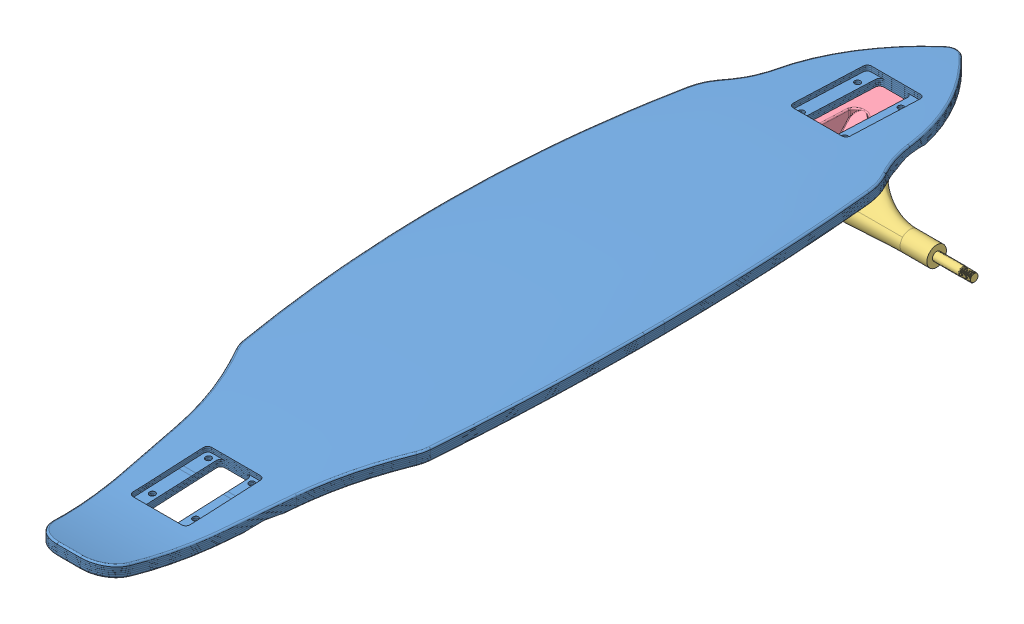
SolidWorks assembly Chamber Complete, configuration Default. Lengths in mm.
Overall size (251.63 119.7 846.49).
12 component instances, 10 part files, 24 mates.
Components (placement in the parent):
- Chamber Deck-2: Chamber Deck [Default] at origin size (203.4 42.87 846.49)
- Truck Cutout-1: Truck Cutout [Default] at (0 15.4335 -251.2196) x (-1 0 0) z (0 0.040365 0.999185) size (652.75 200 200) (hidden)
- Truck Cutout-2: Truck Cutout [Default] at (0 12.2172 374.2126) x (1 0 0) z (0 0.044825 -0.998995) size (652.75 200 200) (hidden)
- Truck-2: Truck [Default] at (27.686 6.0518 -210.5591) x (1 0 0) z (0 -0.0403 -0.999188) size (251.63 82 102.66)
  - Rubber Bushing-1: Rubber Bushing [Default] at (-27.686 9.105 71.5015) x (-0.125245 -0.637726 -0.760012) z (0 0.766044 -0.642788) size (17.78 17.78 15.24)
  - Truck Black-1: Truck Black [Default] at (-27.686 18.8338 63.3381) x (1 0 0) z (0 -0.766044 0.642788) size (251.63 24.69 81.31)
  - Truck Silver-1: Truck Silver [Default] at (-27.686 0 0) x (-1 0 0) z (0 0 -1) size (55.37 68.72 102.66)
  - Large Washer-1: Large Washer [Default] at (-27.686 37.0748 22.445) x (1 0 0) z (0 -0.642788 -0.766044) size (29.97 29.97 4.65)
  - Fat Bushing-1: Fat Bushing [Default] at (-27.686 38.3809 24.0016) x (0.983823 -0.137233 0.115152) z (-0.179144 -0.753652 0.632389) size (25.4 13.76 25.4)
  - Small Bushing-1: Small Bushing [Default] at (-27.686 49.674 37.4601) x (0.221595 -0.747 0.626807) z (0 -0.642788 -0.766044) size (25.4 25.4 13.33)
  - Small Washer-1: Small Washer [Default] at (-27.686 59.5517 49.2319) x (0.99468 -0.07891 0.066213) z (0 0.642788 0.766044) size (23.24 23.24 4.15)
  - 3_8 nut-1: 3_8 nut [94945A218] at (-27.686 59.5517 49.2319) x (1 0 0) z (0 -0.766044 0.642788) size (14.29 7.02 16.5)
Mates (geometry in assembly coordinates):
- Parallel18: parallel: line of Truck Cutout-1 through (23 16.9371 -214) axis (-1 0 0); plane of assembly through (0 0 0) normal (0 0 1)
- Parallel19: parallel: line of Truck Cutout-1 through (23 16.9371 -214) axis (-1 0 0); plane of assembly
- Coincident57: coincident: plane of Truck Cutout-1 through (0 15.4335 -251.2196) normal (-1 0 0); plane of assembly through (0 0 0) normal (1 0 0)
- Coincident58: coincident: face of Chamber Deck-2; point of Truck Cutout-1
- Coincident59: coincident: face of Chamber Deck-2; point of Truck Cutout-1
- Coincident60: coincident: face of Chamber Deck-2; point of Truck Cutout-1
- Parallel20: parallel: line of Truck Cutout-2 through (-23 13.8869 337) axis (1 0 0); plane of assembly
- Parallel21: parallel: line of Truck Cutout-2 through (-23 13.8869 337) axis (1 0 0); plane of assembly
- Coincident63: coincident: plane of Truck Cutout-2 through (0 12.2172 374.2126) normal (1 0 0); plane of assembly through (0 0 0) normal (1 0 0)
- Coincident64: coincident: face of Chamber Deck-2; point of Truck Cutout-2
- Coincident65: coincident: face of Chamber Deck-2; point of Truck Cutout-2
- Coincident66: coincident: face of Chamber Deck-2; point of Truck Cutout-2
- Distance8: distance = 337 mm: line of Truck Cutout-2 through (-23 13.8869 337) axis (1 0 0); plane of assembly
- Distance9: distance = 214 mm: line of Truck Cutout-1 through (23 16.9371 -214) axis (-1 0 0); plane of assembly
- Coincident69: coincident: circle of Chamber Deck-2; circle of ?
- Coincident70: coincident: plane of Chamber Deck-2 through (27 23.6976 341.4442) normal (-1 0 0); plane of ? through (27 8.5922 336.7624) normal (1 0 0)
- Coincident71: coincident: plane of Chamber Deck-2 through (27 26.7675 -218.4004) normal (-1 0 0); plane of ? through (27 12.141 -213.8062) normal (1 0 0)
- Coincident72: coincident: plane of Chamber Deck-2 through (23 11.9796 -217.803) normal (0 0.999185 -0.040365); plane of ? through (0 10.6374 -251.0259) normal (0 -0.999185 0.040365)
- Concentric1: concentric: cylinder of Chamber Deck-2 through (20.55 1.9221 -219.023) axis (0 0.999185 -0.040365) radius 2.75; cylinder of ? through (20.55 11.914 -219.4267) axis (0 0.999185 -0.040365) radius 2.75
- Coincident73: coincident: point of Chamber Deck-2; plane of ? through (49.9427 5.5224 -278.7071) normal (-0.035443 0.999076 -0.024293)
- Coincident74: coincident: point of Chamber Deck-2; plane of ? through (49.9427 5.5224 -278.7071) normal (-0.035443 0.999076 -0.024293)
- Coincident76: coincident: plane of Truck-2 through (0 6.0518 -210.5591) normal (1 0 0); plane of assembly through (0 0 0) normal (1 0 0)
- Coincident77: coincident: point of Chamber Deck-2; plane of Truck-2/Truck Silver-1 through (0 6.0518 -210.5591) normal (0 0.999188 -0.0403)
- Coincident78: coincident: point of Chamber Deck-2; plane of Truck-2/Truck Silver-1 through (0 6.0518 -210.5591) normal (0 0.999188 -0.0403)
